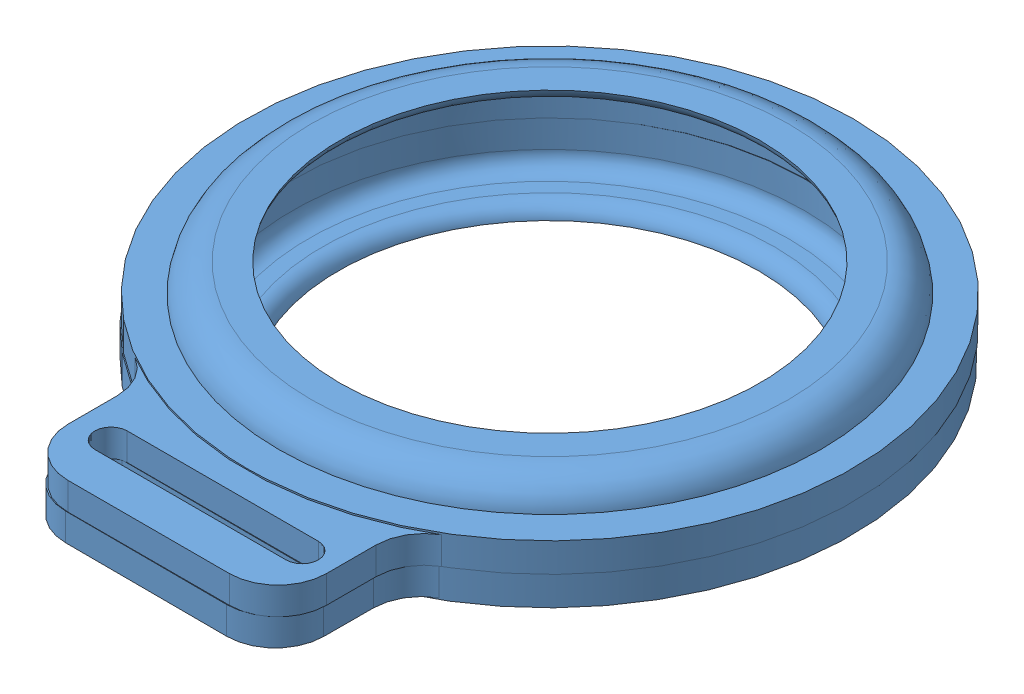
SolidWorks assembly AssempORTA, configuration Default. Lengths in mm.
Overall size (37.62 7 43.67).
2 component instances, 1 part files, 0 mates.
Components (placement in the parent):
- portamoneda-1: portamoneda [Default] at (-17.7984 7.5135 0.0632) size (37.5 3.5 43.57)
- portamoneda-2: portamoneda [Default] at (-17.8514 7.5135 0.0959) x (-0.999996 0 -0.002751) z (-0.002751 0 0.999996) size (37.5 3.5 43.57)
